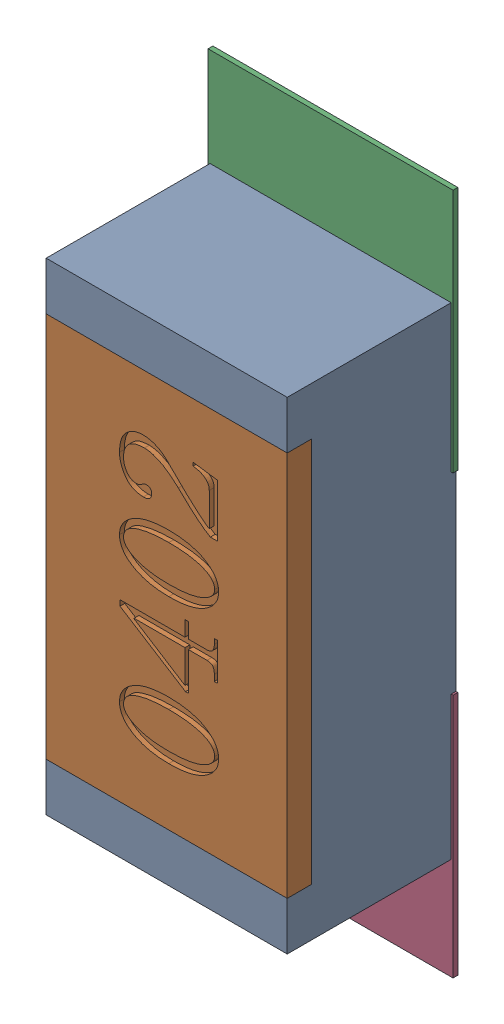
SolidWorks assembly R22, configuration Défaut. Lengths in mm.
Overall size (0.51 1.42 0.35).
5 component instances, 2 part files, 0 mates.
Components (placement in the parent):
- R0402-1: R0402 [Défaut] at (49.9111 -10.0458 0) x (0 1 0) z (0 0 1) size (1 0.5 0.35)
- 6504207776-1: 6504207776 [Défaut] at (49.9109 -9.5958 0) size (0.51 0.51 0.01)
  - Extruded-1: Extruded [Défaut] at origin size (0.51 0.51 0.01)
- 6504207776-2: 6504207776 [Défaut] at (49.9109 -10.5029 0) size (0.51 0.51 0.01)
  - Extruded-1: Extruded [Défaut] at origin size (0.51 0.51 0.01)
